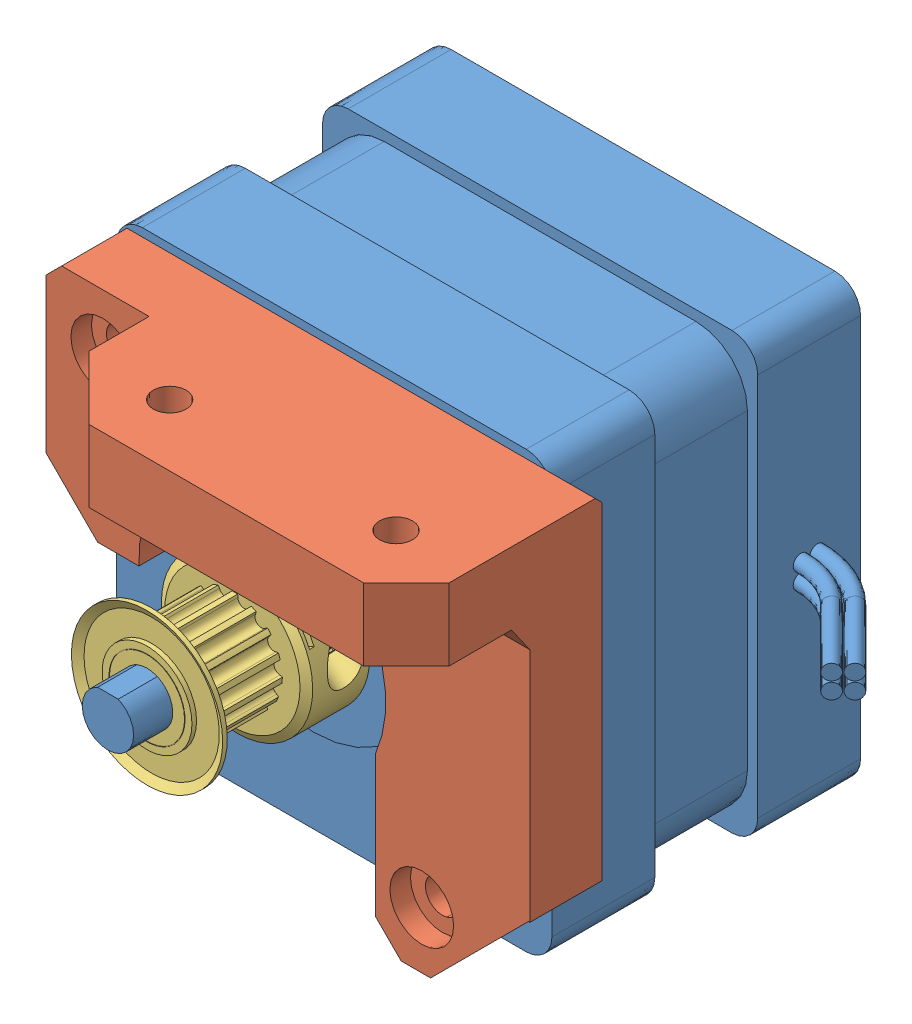
SolidWorks assembly Y Motor Assembly, configuration Default. Lengths in mm.
Overall size (54.71 42.3 52).
3 component instances, 3 part files, 4 mates.
Components (placement in the parent):
- MOTOR_NEMA17_30MM-1: MOTOR_NEMA17_30MM [Default] at (13.874 31.7617 28.9937) size (54.71 42.3 52)
- y-motor-holder-1: y-motor-holder [Default] at (39.874 51.2617 56.9937) x (0 0 -1) z (-1 0 0) size (19 42 47)
- PULLEY_GT2_16T-1: PULLEY_GT2_16T [Default] at (13.874 31.7617 53.8944) x (0.596365 0.802713 0) z (0 0 -1) size (14.7 14.7 14.3)
Mates (geometry in assembly coordinates):
- Concentric1: concentric aligned: circle of MOTOR_NEMA17_30MM-1; cylinder of y-motor-holder-1 through (-1.626 47.2617 76.9937) axis (0 0 -1) radius 1.65
- Concentric2: concentric aligned: circle of MOTOR_NEMA17_30MM-1; circle of y-motor-holder-1
- Coincident1: coincident anti-aligned: plane of MOTOR_NEMA17_30MM-1 through (13.874 31.7617 43.9937) normal (0 0 1); plane of y-motor-holder-1 through (39.874 52.7617 43.9937) normal (0 0 -1)
- Concentric3: concentric aligned: cylinder of MOTOR_NEMA17_30MM-1 through (13.874 31.7617 43.9937) axis (0 0 1) radius 2.5; cylinder of PULLEY_GT2_16T-1 through (13.874 31.7617 47.5944) axis (0 0 1) radius 2.5
